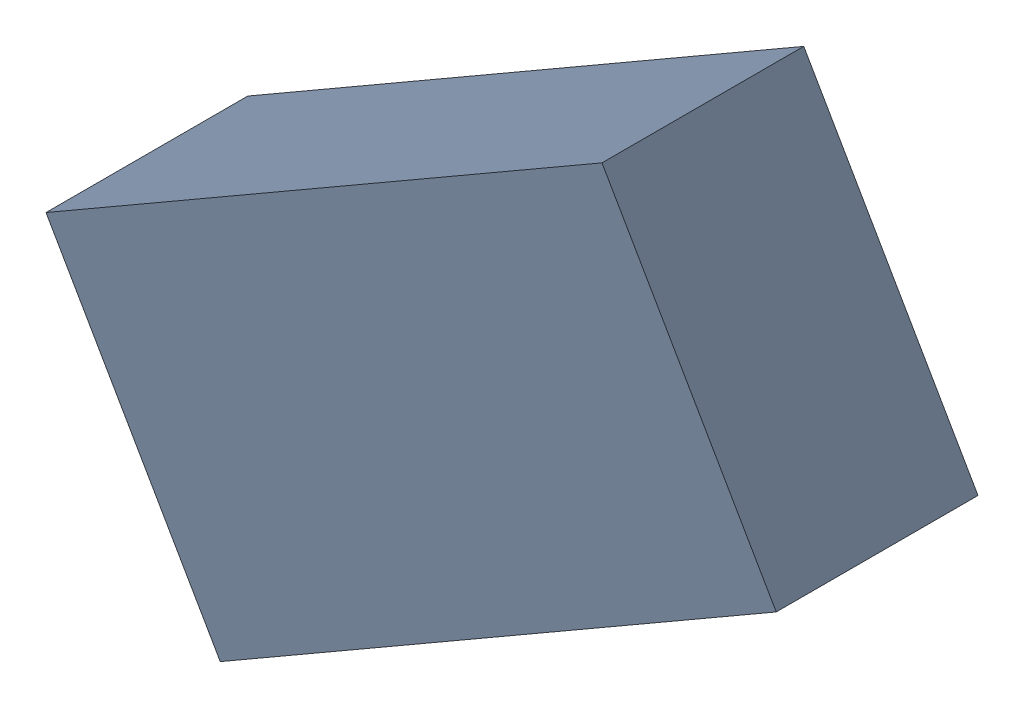
SolidWorks assembly L2_TDA2, configuration Standard. Lengths in mm.
Overall size (1.99 1.7 0.55).
2 component instances, 1 part files, 0 mates.
Components (placement in the parent):
- 885543736-1: 885543736 [Standard] at (51.4623 30.5199 0) size (1.99 1.7 0.55)
  - Extruded_21-1: Extruded_21 [Standard] at origin size (1.99 1.7 0.55)
